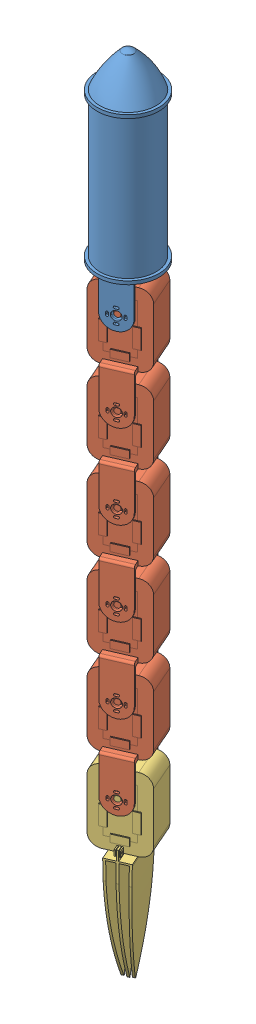
SolidWorks assembly 3fin_eel, configuration 預設. Lengths in mm.
Overall size (60.62 716.27 55.56).
7 component instances, 3 part files, 19 mates.
Components (placement in the parent):
- base_link-1: base_link [預設] at (-66.5632 -1.1579 104.9753) size (55 204.98 55)
- link2-1: link2 [預設] at (-45.8446 -161.6209 204.2877) x (0 1 0) z (0.399282 0 0.916828) size (107 45 40.5)
- link2-2: link2 [預設] at (-45.8446 -236.3209 204.2877) x (0 1 0) z (0.399282 0 0.916828) size (107 45 40.5)
- link2-3: link2 [預設] at (-45.8446 -311.0209 204.2877) x (0 1 0) z (0.399282 0 0.916828) size (107 45 40.5)
- link2-4: link2 [預設] at (-45.8446 -385.7209 204.2877) x (0 1 0) z (0.399282 0 0.916828) size (107 45 40.5)
- link2-5: link2 [預設] at (-45.8446 -460.4209 204.2877) x (0 1 0) z (0.399282 0 0.916828) size (107 45 40.5)
- 3fin_tail-1: 3fin_tail [預設] at (-71.6746 -459.2418 144.6402) x (0 1 0) z (0.399282 0 0.916828) size (170.09 49.51 38.13)
Mates (geometry in assembly coordinates):
- 同軸心1: concentric aligned: cylinder of base_link-1 through (-52.4327 -86.9209 189.16) axis (-0.399282 0 -0.916828) radius 2.7; cylinder of link2-1 through (-51.4345 -86.9209 191.4521) axis (-0.399282 0 -0.916828) radius 2.5
- 平行1: parallel aligned: plane of base_link-1 through (-42.6286 -56.9209 181.6182) normal (0.916828 0 -0.399282); plane of link2-1 through (-19.626 -131.6209 208.1394) normal (0.916828 0 -0.399282)
- 重合/共線/共點1: coincident aligned: circle of base_link-1; plane of link2-1 through (-38.2582 -86.9209 221.7074) normal (0.399282 0 0.916828)
- 重合/共線/共點2: coincident aligned: plane of link2-1 through (-60.8832 -131.6209 226.1071) normal (-0.916828 0 0.399282); plane of link2-2 through (-60.8832 -206.3209 226.1071) normal (-0.916828 0 0.399282)
- 同軸心2: concentric anti-aligned: cylinder of link2-1 through (-53.8302 -161.6209 185.9511) axis (0.399282 0 0.916828) radius 3.7; cylinder of link2-2 through (-51.4345 -161.6209 191.4521) axis (-0.399282 0 -0.916828) radius 2.5
- 平行2: parallel aligned: plane of link2-1 through (-54.7929 -154.5209 186.3704) normal (0 -1 0); plane of link2-2 through (-54.7929 -229.2209 186.3704) normal (0 -1 0)
- 重合/共線/共點4: coincident aligned: plane of link2-1 through (-51.4345 -71.6862 191.4521) normal (-0.399282 0 -0.916828); plane of link2-2 through (-51.4345 -146.3862 191.4521) normal (-0.399282 0 -0.916828)
- 重合/共線/共點5: coincident aligned: plane of link2-2 through (-60.8832 -206.3209 226.1071) normal (-0.916828 0 0.399282); plane of link2-3 through (-60.8832 -281.0209 226.1071) normal (-0.916828 0 0.399282)
- 同軸心3: concentric anti-aligned: cylinder of link2-2 through (-53.8302 -236.3209 185.9511) axis (0.399282 0 0.916828) radius 3.7; cylinder of link2-3 through (-51.4345 -236.3209 191.4521) axis (-0.399282 0 -0.916828) radius 2.5
- 重合/共線/共點6: coincident aligned: plane of link2-2 through (-53.8302 -146.3862 185.9511) normal (-0.399282 0 -0.916828); plane of link2-3 through (-53.8302 -221.0862 185.9511) normal (-0.399282 0 -0.916828)
- 重合/共線/共點7: coincident aligned: plane of link2-3 through (-60.8832 -281.0209 226.1071) normal (-0.916828 0 0.399282); plane of link2-4 through (-60.8832 -355.7209 226.1071) normal (-0.916828 0 0.399282)
- 同軸心4: concentric anti-aligned: cylinder of link2-3 through (-53.8302 -311.0209 185.9511) axis (0.399282 0 0.916828) radius 3.7; cylinder of link2-4 through (-51.4345 -311.0209 191.4521) axis (-0.399282 0 -0.916828) radius 2.5
- 重合/共線/共點8: coincident aligned: plane of link2-3 through (-51.4345 -221.0862 191.4521) normal (-0.399282 0 -0.916828); plane of link2-4 through (-51.4345 -295.7862 191.4521) normal (-0.399282 0 -0.916828)
- 重合/共線/共點10: coincident aligned: plane of link2-4 through (-51.4345 -295.7862 191.4521) normal (-0.399282 0 -0.916828); plane of link2-5 through (-51.4345 -370.4862 191.4521) normal (-0.399282 0 -0.916828)
- 重合/共線/共點11: coincident aligned: plane of link2-4 through (-60.8832 -355.7209 226.1071) normal (-0.916828 0 0.399282); plane of link2-5 through (-60.8832 -430.4209 226.1071) normal (-0.916828 0 0.399282)
- 同軸心6: concentric anti-aligned: cylinder of link2-4 through (-53.8302 -385.7209 185.9511) axis (0.399282 0 0.916828) radius 3.7; cylinder of link2-5 through (-51.4345 -385.7209 191.4521) axis (-0.399282 0 -0.916828) radius 2.5
- 重合/共線/共點12: coincident aligned: plane of link2-5 through (-51.4345 -370.4862 191.4521) normal (-0.399282 0 -0.916828); plane of 3fin_tail-1 through (-51.4345 -445.1862 191.4521) normal (-0.399282 0 -0.916828)
- 同軸心7: concentric anti-aligned: cylinder of link2-5 through (-53.8302 -460.4209 185.9511) axis (0.399282 0 0.916828) radius 3.7; cylinder of 3fin_tail-1 through (-51.4345 -460.4209 191.4521) axis (-0.399282 0 -0.916828) radius 2.5
- 重合/共線/共點13: coincident aligned: plane of link2-5 through (-60.8832 -430.4209 226.1071) normal (-0.916828 0 0.399282); plane of 3fin_tail-1 through (-60.8832 -505.1209 226.1071) normal (-0.916828 0 0.399282)
